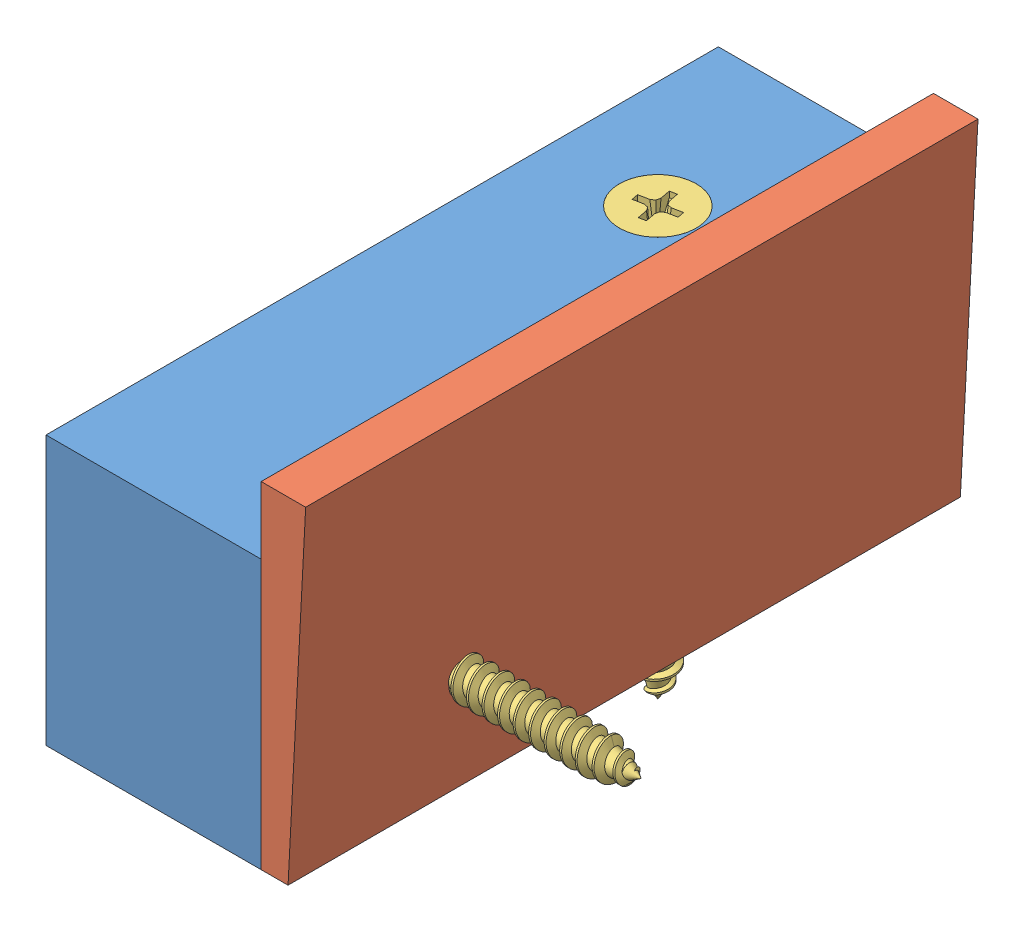
SolidWorks assembly Block Assembly, configuration Default. Lengths in mm.
Overall size (31.75 36.75 50).
4 component instances, 3 part files, 6 mates.
Components (placement in the parent):
- P4-1: P4 [Default] at (681.5529 -205.21 327.1824) x (0 0 -1) z (1 0 0) size (50 20 16)
- A3-1: A3 [Default] at (683.5529 -215.21 302.1824) size (3.31 25 50)
- 90031A117_Phillips Flat Head Screws for Wood-1: 90031A117_Phillips Flat Head Screws for Wood [90031A117] at (681.4279 -207.71 339.6824) x (1 0 0) z (0 0.191546 0.981484) size (31.75 5.71 5.71)
- 90031A117_Phillips Flat Head Screws for Wood-2: 90031A117_Phillips Flat Head Screws for Wood [90031A117] at (673.5529 -211.085 314.6824) x (0 -1 0) z (0.981484 0 -0.191546) size (31.75 5.71 5.71)
Mates (geometry in assembly coordinates):
- Coincident52: coincident aligned: line of P4-1 through (681.5529 -195.21 302.1824) axis (0 -1 0); line of A3-1 through (681.5529 -190.21 302.1824) axis (0 -1 0)
- Coincident53: coincident aligned: line of A3-1 through (681.5529 -215.21 352.1824) axis (0 0 -1); line of P4-1 through (681.5529 -215.21 352.1824) axis (0 0 -1)
- Concentric16: concentric aligned: circle of P4-1; cylinder of 90031A117_Phillips Flat Head Screws for Wood-1 through (665.5529 -207.71 339.6824) axis (-1 0 0) radius 1.4224
- Coincident57: coincident aligned: plane of P4-1 through (665.5529 -205.21 327.1824) normal (-1 0 0); plane of 90031A117_Phillips Flat Head Screws for Wood-1 through (665.5529 -207.71 339.6824) normal (-1 0 0)
- Concentric17: concentric aligned: circle of P4-1; cylinder of 90031A117_Phillips Flat Head Screws for Wood-2 through (673.5529 -195.21 314.6824) axis (0 1 0) radius 1.4224
- Coincident58: coincident aligned: plane of P4-1 through (665.5529 -195.21 352.1824) normal (0 1 0); plane of 90031A117_Phillips Flat Head Screws for Wood-2 through (673.5529 -195.21 314.6824) normal (0 1 0)
